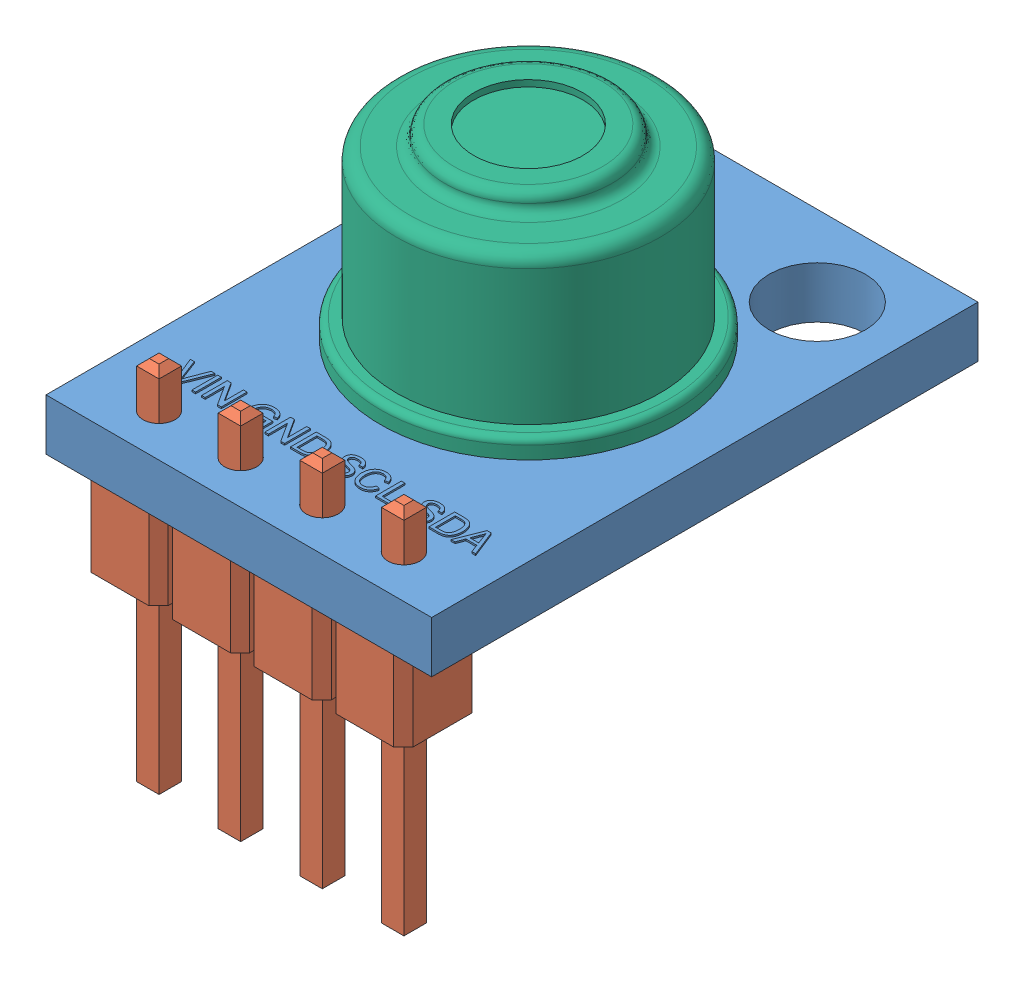
SolidWorks assembly HW-691, configuration По умолчанию. Lengths in mm.
Overall size (12 16 17).
11 component instances, 6 part files, 16 mates.
Components (placement in the parent):
- IRTS_pcb-1: IRTS_pcb [По умолчанию] at (11.2363 9.4342 6.6002) size (12 1.66 17)
- IRTS_pin-1: IRTS_pin [По умолчанию] at (12.2376 9.4342 17.2354) x (-1 0 0) z (0 0 1) size (2.4 11.6 2.44)
- IRTS_pin-2: IRTS_pin [По умолчанию] at (9.6976 9.4342 17.2354) x (-1 0 0) z (0 0 1) size (2.4 11.6 2.44)
- IRTS_pin-3: IRTS_pin [По умолчанию] at (7.1576 9.4342 17.2354) x (-1 0 0) z (0 0 1) size (2.4 11.6 2.44)
- IRTS_pin-4: IRTS_pin [По умолчанию] at (4.6176 9.4342 17.2354) x (-1 0 0) z (0 0 1) size (2.4 11.6 2.44)
- IRTS_reistor-1: IRTS_reistor [По умолчанию] at (11.2328 9.4342 13.5712) x (-1 0 0) z (0 0 1) size (0.8 0.41 1.6)
- IRTS_reistor-2: IRTS_reistor [По умолчанию] at (9.6328 9.4342 13.5712) x (-1 0 0) z (0 0 1) size (0.8 0.41 1.6)
- IRTS_capacitor-1: IRTS_capacitor [По умолчанию] at (11.6097 9.4342 12.9574) x (0 0 -1) z (-1 0 0) size (1.6 0.81 0.8)
- IRTS_Transistor-1: IRTS_Transistor [По умолчанию] at (8.5964 9.4342 12.5137) x (0 0 -1) z (-1 0 0) size (2.7 1.6 2.5)
- IRTS_capacitor-2: IRTS_capacitor [По умолчанию] at (5.3097 9.4342 12.9574) x (0 0 -1) z (-1 0 0) size (1.6 0.81 0.8)
- IRTS_IRSensor-1: IRTS_IRSensor [По умолчанию] at (9.8879 12.9676 8.8112) size (9.2 8.87 9.2)
Mates (geometry in assembly coordinates):
- Совпадение1: coincident anti-aligned: plane of IRTS_pcb-1 through (11.2363 9.4342 6.6002) normal (0 -1 0); plane of IRTS_pin-1 through (12.2376 9.4342 17.2354) normal (0 1 0)
- Параллельность1: parallel aligned: plane of IRTS_pcb-1 through (3.8795 11.0342 17.8112) normal (0 0 1); plane of IRTS_pin-1 through (14.5795 6.8342 17.694) normal (0 0 1)
- Концентричный1: concentric anti-aligned: cylinder of IRTS_pcb-1 through (13.6795 11.0342 16.474) axis (0 -1 0) radius 0.5; line of IRTS_pin-1 through (13.6795 0.8342 16.474) axis (0 1 0)
- Совпадение3: coincident anti-aligned: plane of IRTS_pcb-1 through (11.2363 9.4342 6.6002) normal (0 -1 0); plane of IRTS_reistor-1 through (11.2328 9.4342 13.5712) normal (0 1 0)
- Расстояние1: distance = 0.7 mm aligned: plane of IRTS_pcb-1 through (15.8795 11.0342 0.8112) normal (1 0 0); plane of IRTS_reistor-1 through (15.1795 9.0342 12.2112) normal (1 0 0)
- Расстояние2: distance = 4 mm aligned: plane of IRTS_pcb-1 through (3.8795 11.0342 17.8112) normal (0 0 1); plane of IRTS_reistor-1 through (15.1795 9.0342 13.8112) normal (0 0 1)
- Совпадение6: coincident anti-aligned: plane of IRTS_pcb-1 through (11.2363 9.4342 6.6002) normal (0 -1 0); plane of IRTS_capacitor-1 through (11.6097 9.4342 12.9574) normal (0 1 0)
- Расстояние3: distance = 0.8 mm anti-aligned: plane of IRTS_capacitor-1 through (11.9795 8.6342 13.8112) normal (1 0 0); plane of IRTS_reistor-2 through (12.7795 9.0342 12.2112) normal (-1 0 0)
- Совпадение8: coincident aligned: plane of IRTS_reistor-2 through (13.5795 9.0342 12.2112) normal (0 0 -1); plane of IRTS_capacitor-1 through (11.9795 8.6342 12.2112) normal (0 0 -1)
- Совпадение9: coincident anti-aligned: plane of IRTS_pcb-1 through (11.2363 9.4342 6.6002) normal (0 -1 0); plane of IRTS_Transistor-1 through (8.5964 9.4342 12.5137) normal (0 1 0)
- Расстояние4: distance = 2.1 mm anti-aligned: plane of IRTS_Transistor-1 through (9.0795 7.8342 14.3265) normal (1 0 0); plane of IRTS_capacitor-1 through (11.1795 8.6342 13.8112) normal (-1 0 0)
- Концентричный2: concentric anti-aligned: cylinder of IRTS_pcb-1 through (8.0379 11.0342 10.6612) axis (0 -1 0) radius 0.5; axis of IRTS_IRSensor-1 through (8.0379 7.9676 10.6612) axis (0 1 0)
- Параллельность4: parallel anti-aligned: cylinder of IRTS_pcb-1 through (11.7295 11.0342 6.9612) axis (0 -1 0) radius 0.5; cylinder of IRTS_IRSensor-1 through (11.7379 7.9676 6.9612) axis (0 1 0) radius 0.25
- Совпадение11: coincident anti-aligned: plane of IRTS_pcb-1 through (11.2363 11.0342 6.6002) normal (0 1 0); circle of IRTS_IRSensor-1
- Концентричный6: concentric anti-aligned: cylinder of IRTS_pcb-1 through (8.0379 11.0342 6.9612) axis (0 -1 0) radius 0.5; cylinder of IRTS_IRSensor-1 through (8.0379 7.9676 6.9612) axis (0 1 0) radius 0.25
- Расстояние5: distance = 0.1153 mm anti-aligned: plane of IRTS_Transistor-1 through (9.0795 8.6342 13.9265) normal (0 0 -1); plane of IRTS_capacitor-1 through (11.9795 8.6342 13.8112) normal (0 0 1)
